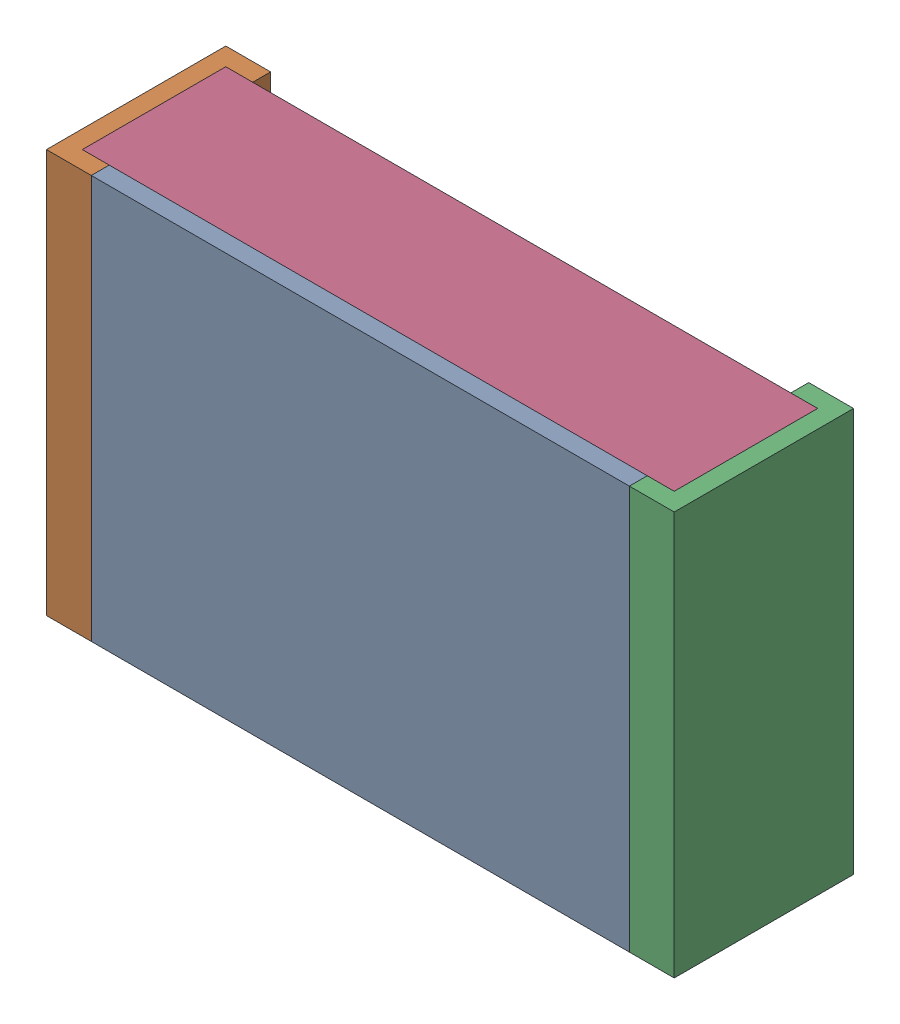
SolidWorks assembly R17, configuration По умолчанию. Lengths in mm.
Overall size (2.1 1.35 0.6).
5 component instances, 3 part files, 0 mates.
Components (placement in the parent):
- RESC2012X06N.step-1: RESC2012X06N.step [По умолчанию] at origin size (2.1 1.35 0.6)
  - RESC2012X06N.step-Part-1-1: RESC2012X06N.step-Part-1 [По умолчанию] at (-0.9 -0.675 0.54) size (1.8 1.35 0.06)
  - RESC2012X06N.step-Part-2-1: RESC2012X06N.step-Part-2 [По умолчанию] at (-1.05 -0.675 0) size (0.15 1.35 0.6)
  - RESC2012X06N.step-Part-2-2: RESC2012X06N.step-Part-2 [По умолчанию] at (1.05 0.675 0) x (-1 0 0) z (0 0 1) size (0.15 1.35 0.6)
  - RESC2012X06N.step-Part-3-1: RESC2012X06N.step-Part-3 [По умолчанию] at (-1.05 -0.675 0) size (1.98 1.35 0.48)
